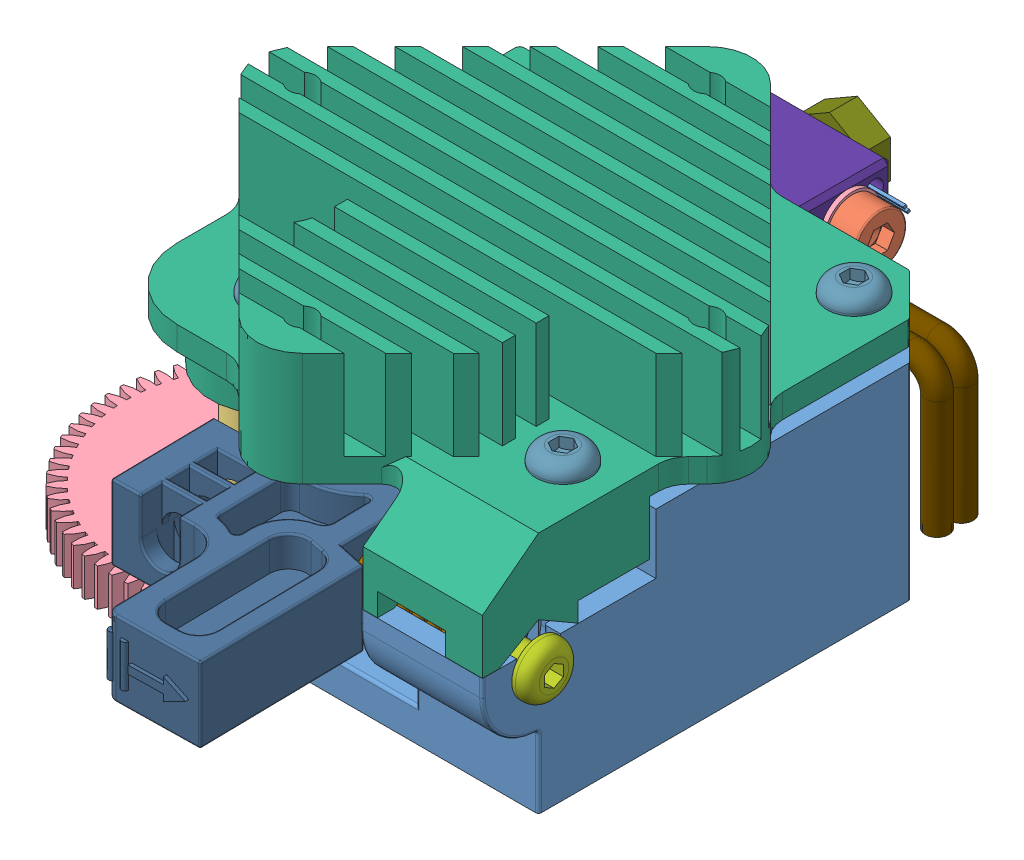
SolidWorks assembly e3d titan areo 1.75, configuration Default. Lengths in mm.
Overall size (62.33 43.86 89.93).
32 component instances, 23 part files, 0 mates.
Components (placement in the parent):
- e3d titan areo 1.75.step-1: e3d titan areo 1.75.step [Default] at origin size (64.3 55.51 89.93)
  - Base.step-1: Base.step [Default] at origin size (46 23.41 49.98)
  - 9x5x3mm bearing.step-1: 9x5x3mm bearing.step [Default] at (-15.5 4 15.5) x (1 0 0) z (0 -1 0) size (9 9 3)
  - hobbed wheel.step-1: hobbed wheel.step [Default] at (-15.5 1.6 15.5) x (-0.447437 0 0.894315) z (0 1 0) size (8.6 8.58 20.6)
  - filament gear.step-1: filament gear.step [Default] at (-15.5 8.55 15.5) x (-0.894315 0 -0.447437) z (0 -1 0) size (34 34 4)
  - motor gear.step-1: motor gear.step [Default] at (0 8.5 0) x (-0.681998 0 -0.731354) z (0 -1 0) size (11.99 12.02 9)
  - cover.step-1: cover.step [Default] at (0 24.9 0) x (1 0 0) z (0 0 -1) size (52.63 28.16 55.14)
  - 9x5x3mm bearing.step-2: 9x5x3mm bearing.step [Default] at (-15.5 22.8 15.5) x (1 0 0) z (0 -1 0) size (9 9 3)
  - m3x8.step-1: m3x8.step [Default] at (20.7 13.6 23.3) x (0 0 1) z (0 1 0) size (5.69 9.65 5.69)
  - M3 nut.step-1: M3 nut.step [Default] at (16.7 13.6 23.3) x (0 1 0) z (0 0 1) size (5.49 2.44 6.31)
  - idler spring.step-1: idler spring.step [Default] at (14.287 13.6 23.3) x (0 0 1) z (-1 0 0) size (6.44 6.46 12.03)
  - tensioner.step-1: tensioner.step [Default] at (0 13.6 0) x (0 -1 0) z (0.017452 0 0.999848) size (8.2 21.5 50.88)
  - idler bearing pin.step-1: idler bearing pin.step [Default] at (-5.2287 9.6 15.5936) x (0.999848 0 -0.017452) z (0 1 0) size (3 3 9)
  - idler bearing.step-1: idler bearing.step [Default] at (-5.2287 13.6 15.5936) x (0.999848 0 -0.017452) z (0 1 0) size (10 10 4)
  - guide tube.step-1: guide tube.step [Default] at (-10.9 13.6 -7.9) x (-1 0 0) z (0 0 1) size (10.9 16.1 22.03)
  - ISO 7380 - M3 x 28 v1.step-1: ISO 7380 - M3 x 28 v1.step [Default] at (-15.5 25.94 15.5) x (0 -1 0) z (0 0 1) size (14.65 5.7 5.7)
  - ISO 7380 - M3 x 28 v1.step-2: ISO 7380 - M3 x 28 v1.step [Default] at (15.5 25.94 15.5) x (0 -1 0) z (0 0 1) size (14.65 5.7 5.7)
  - ISO 7380 - M3 x 28 v1.step-3: ISO 7380 - M3 x 28 v1.step [Default] at (15.5 25.94 -15.5) x (0 -1 0) z (0 0 1) size (14.65 5.7 5.7)
  - ISO 7380 - M3 x 28 v1.step-4: ISO 7380 - M3 x 28 v1.step [Default] at (-21.7 25.94 -14.7) x (0 -1 0) z (0 0 -1) size (14.65 5.7 5.7)
  - Fan 40 X 40 X 10 v4.step-1: Fan 40 X 40 X 10 v4.step [Default] at (-2.3 40.465 3.8274) x (0.707107 0 0.707107) z (-0.707107 0 0.707107) size (40 10.58 40) (hidden)
  - E3D v6 HotEnd - Heatbreak.step-1: E3D v6 HotEnd - Heatbreak.step [Default] at (-10.9 13.6 -31.7812) x (0 1 0) z (0 0 -1) size (7 7 21.9)
  - E3D v6 HotEnd - Nozzle.step-1: E3D v6 HotEnd - Nozzle.step [Default] at (-10.9 13.6 -42.2812) x (0 1 0) z (0 0 -1) size (8.08 7 12.5)
  - E3D v6 HotEnd - Heat Block.step-1: E3D v6 HotEnd - Heat Block.step [Default] at (-2.9 -1.9 -38.0312) x (0 1 0) z (1 0 0) size (20 11.5 16)
  - Ceramic Cartridge Heater.step-1: Ceramic Cartridge Heater.step [Default] at (-0.9 6.6 -34.0312) x (0 0 1) z (1 0 0) size (6 18 29.25)
  - Thermistor.step-1: Thermistor.step [Default] at (-7 16.1 -36.0312) x (0 -0.5 0.866025) z (-1 0 0) size (1.5 1.5 7.6)
  - HEXAGON SOCKET HEAD CAP SCREWS_SCB3-4.step-1: HEXAGON SOCKET HEAD CAP SCREWS_SCB3-4.step [Default] at (-2.4 14.6 -33.2312) x (0 1 0) z (1 0 0) size (5.5 5.5 7)
  - HEXAGON SOCKET HEAD CAP SCREWS_SCB3-10.step-1: HEXAGON SOCKET HEAD CAP SCREWS_SCB3-10.step [Default] at (-10.9 0.6 -38.0312) x (0 1 0) z (0 0 -1) size (5.5 5.5 13)
  - Flat Washers_PWF3.step-1: Flat Washers_PWF3.step [Default] at (-2.4 14.6 -33.2312) x (0 1 0) z (1 0 0) size (6 6 0.5)
  - ISO 7380 - M3 x 28 v1.step-5: ISO 7380 - M3 x 28 v1.step [Default] at (-2.3 45.465 26.4548) x (0 -1 0) z (0.707107 0 0.707107) size (14.65 5.7 5.7) (hidden)
  - ISO 7380 - M3 x 28 v1.step-6: ISO 7380 - M3 x 28 v1.step [Default] at (-24.9274 45.465 3.8274) x (0 -1 0) z (0.707107 0 0.707107) size (14.65 5.7 5.7) (hidden)
  - ISO 7380 - M3 x 28 v1.step-7: ISO 7380 - M3 x 28 v1.step [Default] at (-2.3 45.465 -18.8) x (0 -1 0) z (0.707107 0 0.707107) size (14.65 5.7 5.7) (hidden)
  - ISO 7380 - M3 x 28 v1.step-8: ISO 7380 - M3 x 28 v1.step [Default] at (20.3274 45.465 3.8274) x (0 -1 0) z (0.707107 0 0.707107) size (14.65 5.7 5.7) (hidden)
